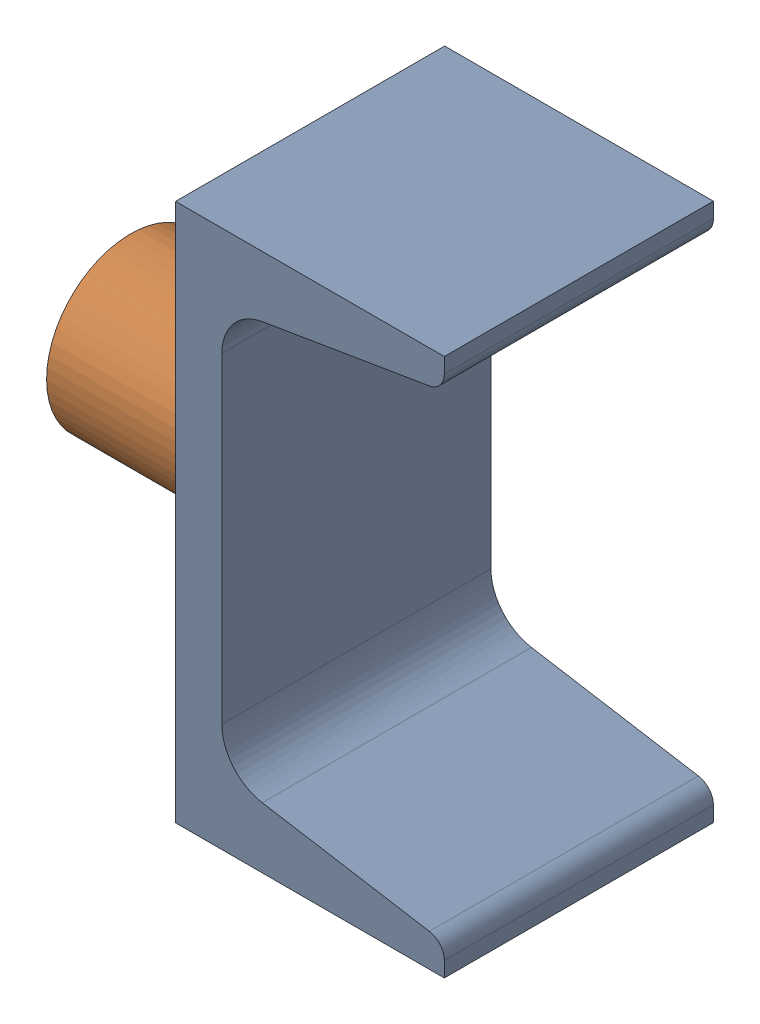
SolidWorks assembly 01-113-00-0, configuration Default. Lengths in mm.
Overall size (63.45 76.2 38.1).
2 component instances, 2 part files, 0 mates.
Components (placement in the parent):
- 01-112-00-0-1: 01-112-00-0 [Default] at (-117.0124 -34.5535 49.2974) size (38.05 76.2 38.1)
- 01-111-00-0-1: 01-111-00-0 [Default] at (-142.4124 3.5465 49.2974) x (0 -1 0) z (0 0 1) size (23.81 25.4 23.81)
